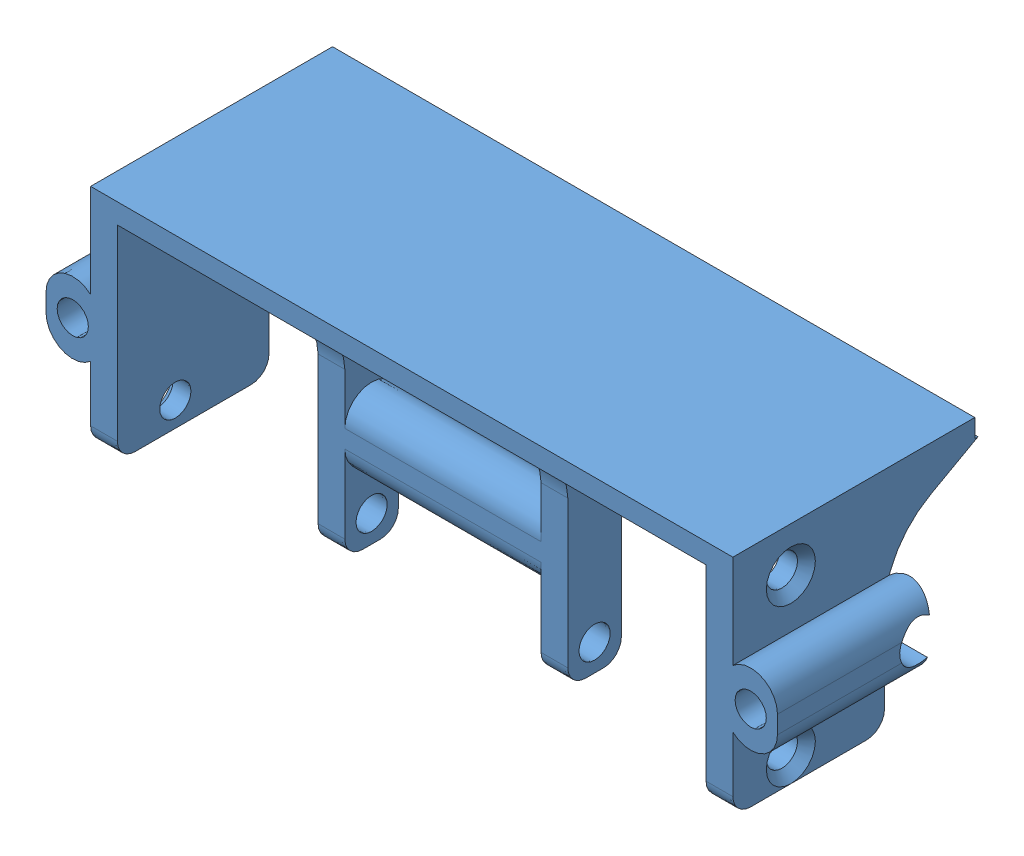
SolidWorks assembly Llantas Traseras, configuration Predeterminado. Lengths in mm.
Overall size (82 61.5 47.12).
4 component instances, 4 part files, 18 mates.
Components (placement in the parent):
- 0-1: 0 [Predeterminado] at (-2.6726 -0.0247 28) size (72 25.5 27.12) (hidden)
- 1L-1: 1L [Predeterminado] at (35.3274 -0.0247 37.5) x (0 0 -1) z (1 0 0) size (27.12 23 8) (hidden)
- 1R-1: 1R [Predeterminado] at (-40.6726 -0.0247 37.5) x (0 0 -1) z (1 0 0) size (27.12 23 8) (hidden)
- SoporteLlantasTraseras(Fusionadas)-1: SoporteLlantasTraseras(Fusionadas) [Predeterminado] at (-2.6726 13.7253 28) x (1 0 0) z (0 1 0) size (82 47.12 69.5)
Mates (geometry in assembly coordinates):
- Concéntrica1: concentric: circle of assembly; circle of assembly; circle of 0-1; circle of 1L-1
- Concéntrica2: concentric: circle of assembly; circle of assembly; circle of 0-1; circle of 1L-1
- Concéntrica3: concentric: circle of assembly; circle of assembly; circle of 0-1; circle of 1R-1
- Concéntrica4: concentric: circle of assembly; circle of assembly; circle of 0-1; circle of 1R-1
- Distancia1: distance = 76 mm: cylinder of assembly; cylinder of assembly; cylinder of 1R-1 through (-40.6726 -0.0247 22.5) axis (0 0 1) radius 1.75; cylinder of 1L-1 through (35.3274 -0.0247 22.5) axis (0 0 1) radius 1.75
- Ancho1: width: plane of assembly; plane of assembly; plane of assembly; plane of assembly; plane of 1R-1 through (-38.6726 -0.0247 37.5) normal (-1 0 0); plane of 1L-1 through (33.3274 -0.0247 37.5) normal (1 0 0); plane of 0-1 through (11.3274 -1.0247 28) normal (1 0 0); plane of 0-1 through (-16.6726 -1.0247 28) normal (-1 0 0)
- EnPosición1: in place: plane of 0-1 through (-2.6726 13.7253 28) normal (0 1 0); plane of ? through (0 13.7253 0) normal (0 1 0); moOrthogonalPlaneRef_w of 0-1 through (-2.6726 13.7253 28) normal (0 1 0); plane of ? through (0 13.7253 0) normal (0 0 -1); plane of 0-1 through (-2.6726 13.7253 28) normal (0 1 0); plane of ? through (0 13.7253 0) normal (1 0 0); plane of 0-1 through (-2.6726 13.7253 28) normal (0 1 0); unknown of SoporteLlantasTraseras(Fusionadas)-1
- Coincidente1: coincident: plane of assembly; plane of assembly; plane of 0-1; plane of ?
- Coincidente2: coincident: plane of 0-1 through (-2.6726 13.7253 28) normal (0 0 -1); plane of SoporteLlantasTraseras(Fusionadas)-1 through (-2.6726 13.7253 28) normal (0 0 -1)
- Coincidente3: coincident: plane of 0-1 through (-2.6726 13.7253 28) normal (-1 0 0); plane of SoporteLlantasTraseras(Fusionadas)-1 through (-2.6726 13.7253 28) normal (1 0 0)
- EnPosición2: in place: plane of 0-1 through (-2.6726 13.7253 28) normal (0 1 0); plane of ? through (0 13.7253 0) normal (0 1 0); plane of 0-1 through (-2.6726 13.7253 28) normal (0 1 0); plane of ? through (0 13.7253 0) normal (0 0 -1); plane of 0-1 through (-2.6726 13.7253 28) normal (0 1 0); plane of ? through (0 13.7253 0) normal (1 0 0); plane of 0-1 through (-2.6726 13.7253 28) normal (0 1 0); unknown of SoporteLlantasTraseras(Fusionadas)-1
- Coincidente4: coincident: plane of assembly; plane of assembly; plane of 0-1; plane of ?
- Coincidente5: coincident: plane of 0-1 through (-2.6726 13.7253 28) normal (0 0 -1); plane of SoporteLlantasTraseras(Fusionadas)-1 through (-2.6726 13.7253 28) normal (0 0 -1)
- Coincidente6: coincident: plane of 0-1 through (-2.6726 13.7253 28) normal (-1 0 0); plane of SoporteLlantasTraseras(Fusionadas)-1 through (-2.6726 13.7253 28) normal (1 0 0)
- EnPosición3: in place: plane of 0-1 through (-2.6726 13.7253 28) normal (0 1 0); plane of ? through (0 13.7253 0) normal (0 1 0); plane of 0-1 through (-2.6726 13.7253 28) normal (0 1 0); plane of ? through (0 13.7253 0) normal (0 0 -1); plane of 0-1 through (-2.6726 13.7253 28) normal (0 1 0); plane of ? through (0 13.7253 0) normal (1 0 0); plane of 0-1 through (-2.6726 13.7253 28) normal (0 1 0); unknown of SoporteLlantasTraseras(Fusionadas)-1
- Coincidente7: coincident: plane of assembly; plane of assembly; plane of 0-1; plane of SoporteLlantasTraseras(Fusionadas)-1
- Coincidente8: coincident: plane of assembly; plane of assembly; moOrthogonalPlaneRef_w of 0-1 through (-2.6726 13.7253 28) normal (0 0 -1); plane of SoporteLlantasTraseras(Fusionadas)-1 through (-2.6726 13.7253 28) normal (0 0 -1)
- Coincidente9: coincident: plane of assembly; plane of assembly; moOrthogonalPlaneRef_w of 0-1 through (-2.6726 13.7253 28) normal (-1 0 0); plane of SoporteLlantasTraseras(Fusionadas)-1 through (-2.6726 13.7253 28) normal (1 0 0)
